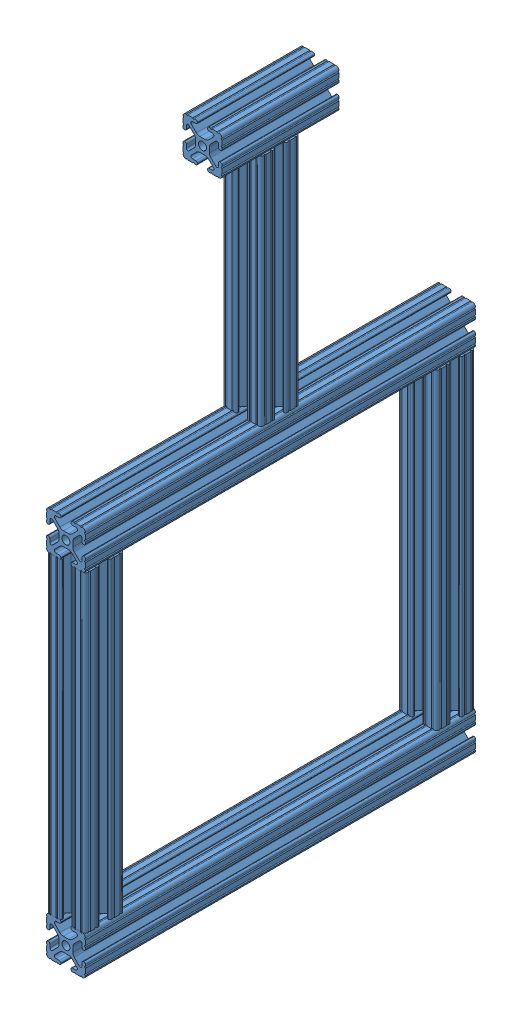
SolidWorks assembly chimney-puller, configuration Default. Lengths in mm.
Overall size (25.4 431.8 254).
6 component instances, 1 part files, 15 mates.
Components (placement in the parent):
- 8020-1010 X 12-1: 8020-1010 X 12 [10] at origin size (25.4 25.4 254)
- 8020-1010 X 12-2: 8020-1010 X 12 [8] at (0 -12.7 -12.7) x (1 0 0) z (0 1 0) size (25.4 25.4 203.2)
- 8020-1010 X 12-3: 8020-1010 X 12 [8] at (0 -12.7 -241.3) x (1 0 0) z (0 1 0) size (25.4 25.4 203.2)
- 8020-1010 X 12-4: 8020-1010 X 12 [10] at (0 -228.6 0) size (25.4 25.4 254)
- 8020-1010 X 12-5: 8020-1010 X 12 [6] at (0 165.1 -127) x (1 0 0) z (0 1 0) size (25.4 25.4 152.4)
- 8020-1010 X 12-6: 8020-1010 X 12 [3] at (0 177.8 -165.1) x (1 0 0) z (0 0 -1) size (25.4 25.4 76.2)
Mates (geometry in assembly coordinates):
- Coincident3: coincident anti-aligned: plane of 8020-1010 X 12-1 through (6.3331 -12.7 -254) normal (0 -1 0); plane of 8020-1010 X 12-2 through (-1.7093 -12.7 -5.0292) normal (0 1 0)
- Coincident4: coincident aligned: plane of 8020-1010 X 12-1 through (-1.7093 -7.6708 0) normal (0 0 1); plane of 8020-1010 X 12-2 through (6.3331 -215.9 0) normal (0 0 1)
- Coincident5: coincident aligned: plane of 8020-1010 X 12-1 through (12.7 -9.5504 -254) normal (1 0 0); plane of 8020-1010 X 12-2 through (12.7 -215.9 -3.1496) normal (1 0 0)
- Coincident6: coincident aligned: plane of 8020-1010 X 12-1 through (-1.7093 -7.6708 -254) normal (0 0 -1); plane of 8020-1010 X 12-3 through (9.5504 -215.9 -254) normal (0 0 -1)
- Coincident7: coincident aligned: plane of 8020-1010 X 12-1 through (12.7 -9.5504 -254) normal (1 0 0); plane of 8020-1010 X 12-3 through (12.7 -215.9 -247.6331) normal (1 0 0)
- Coincident8: coincident anti-aligned: plane of 8020-1010 X 12-1 through (6.3331 -12.7 -254) normal (0 -1 0); plane of 8020-1010 X 12-3 through (-1.7093 -12.7 -233.6292) normal (0 1 0)
- Coincident9: coincident aligned: plane of 8020-1010 X 12-3 through (9.5504 -215.9 -254) normal (0 0 -1); plane of 8020-1010 X 12-4 through (-1.7093 -236.2708 -254) normal (0 0 -1)
- Coincident10: coincident aligned: plane of 8020-1010 X 12-3 through (12.7 -215.9 -247.6331) normal (1 0 0); plane of 8020-1010 X 12-4 through (12.7 -222.2669 -254) normal (1 0 0)
- Coincident11: coincident anti-aligned: plane of 8020-1010 X 12-3 through (-1.7093 -215.9 -233.6292) normal (0 -1 0); plane of 8020-1010 X 12-4 through (9.5504 -215.9 -254) normal (0 1 0)
- Coincident12: coincident aligned: plane of 8020-1010 X 12-1 through (12.7 6.3331 -254) normal (1 0 0); plane of 8020-1010 X 12-5 through (12.7 12.7 -133.3331) normal (1 0 0)
- Coincident13: coincident anti-aligned: plane of 8020-1010 X 12-5 through (-1.7093 12.7 -119.3292) normal (0 -1 0); plane of 8020-1010 X 12-1 through (9.5504 12.7 -254) normal (0 1 0)
- Distance2: distance = 127 mm aligned: plane of 8020-1010 X 12-5 through (0 165.1 -127) normal (0 0 -1); plane of 8020-1010 X 12-1 through (-1.7093 -7.6708 -254) normal (0 0 -1)
- Coincident15: coincident anti-aligned: plane of 8020-1010 X 12-5 through (-1.7093 165.1 -119.3292) normal (0 1 0); plane of 8020-1010 X 12-6 through (9.5504 165.1 -88.9) normal (0 -1 0)
- Coincident16: coincident aligned: plane of 8020-1010 X 12-5 through (12.7 12.7 -133.3331) normal (1 0 0); plane of 8020-1010 X 12-6 through (12.7 187.3504 -88.9) normal (1 0 0)
- Distance3: distance = 38.1 mm aligned: plane of 8020-1010 X 12-5 through (0 165.1 -127) normal (0 0 -1); plane of 8020-1010 X 12-6 through (-1.7093 185.4708 -165.1) normal (0 0 -1)
